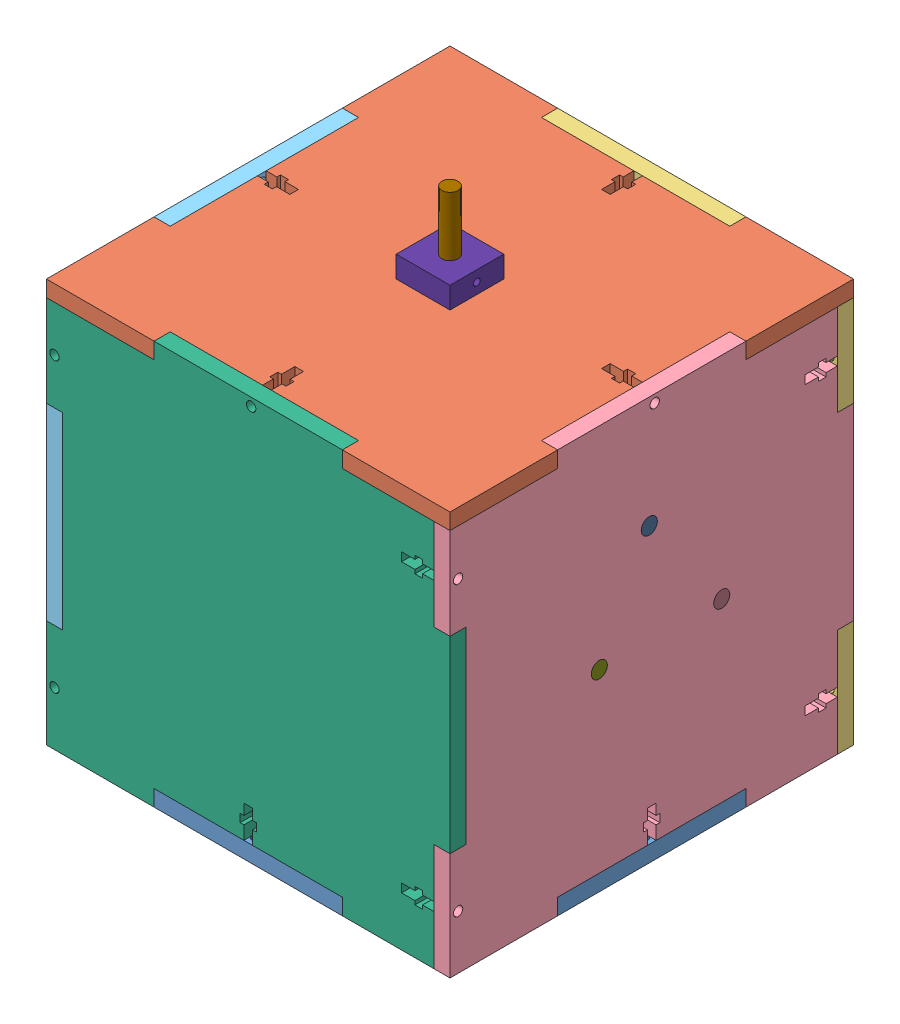
SolidWorks assembly Box_Assem, configuration Default. Lengths in mm.
Overall size (150 180 180).
35 component instances, 20 part files, 60 mates.
Components (placement in the parent):
- base-1: base [Default] at (64.477 69.4479 114.6209) size (150 6 150)
- lid-1: lid [Default] at (64.477 213.4479 114.6209) size (150 6 150)
- side_IN-1: side_IN [Default] at (67.477 141.4479 39.6209) size (150 150 6)
- side_3-1: side_3 [Default] at (139.477 141.4479 117.6209) x (0 0 1) z (-1 0 0) size (150 150 6)
- side_2-1: side_2 [Default] at (-10.523 141.4479 111.6209) x (0 0 -1) z (1 0 0) size (150 150 6)
- side_1-6: side_1 [Default] at (61.477 141.4479 189.6209) x (-1 0 0) z (0 0 -1) size (150 150 6)
- Part7^Box_Assem-1: Part7^Box_Assem [Default] at origin (virtual)
- Part9^Box_Assem-1: Part9^Box_Assem [Default] at origin (virtual)
- Assem5^Box_Assem-1: Assem5^Box_Assem [Default] at (178.5717 30.91 0) x (0.331384 0.943496 0) z (0 0 1) size (32.65 32.7 65.5) (virtual)
  - Input shaft-1: Input shaft [Default] at (-47.3106 246.4446 73.8642) x (-0.962325 0.271902 0) z (0 0 -1) size (6 6 64.24)
  - straight bevel pinion_am-1: straight bevel pinion_am [Metric - Straight bevel pinion 1.5M14PT 14GT 20PA 9FW ---14O75H20MD6N] at (67.477 141.4479 66.545) x (0 0 1) z (-0.653712 0.756744 0) size (16.5 22.92 23.41)
- Assem4^Box_Assem-1: Assem4^Box_Assem [Default] at (65.1602 0 246.1305) x (-0.874102 0 -0.485743) z (0.485743 0 -0.874102) size (29.77 58.5 29.46) (virtual)
  - output shaft^Assem4_Box_Assem-1: output shaft^Assem4_Box_Assem [Default] at (204.857 192.2046 181.6581) x (0.612932 0 0.790136) z (0 1 0) size (6 6 57.24) (virtual)
  - straight bevel pinion_am-1: straight bevel pinion_am [Metric - Straight bevel pinion 1.5M14PT 14GT 20PA 9FW ---14O75H20MD6N] at (64.477 199.5237 114.6209) x (0 -1 0) z (-0.94154 0 0.336902) size (16.5 22.92 23.41)
- Assem3^Box_Assem-1: Assem3^Box_Assem [Default] at (0 21.4454 258.8037) x (1 0 0) z (0 0.968014 0.250897) size (150 53.02 53.02) (virtual)
  - transmission shaft^Assem3_Box_Assem-1: transmission shaft^Assem3_Box_Assem [Default] at (-10.523 -19.5749 -105.5679) x (0 -0.566583 -0.824005) z (1 0 0) size (6 6 150) (virtual)
  - straight bevel gear_am-1: straight bevel gear_am [Metric - Straight bevel gear 1.5M 28GT 14PT 20PA 12FW ---28O32H20MD6N] at (77.5489 177.9396 115.5457) x (-1 0 0) z (0 0.275661 -0.961255) size (15.67 42.87 42.87)
  - spur gear_am-1: spur gear_am [Metric - Spur gear 1.5M 28T 20PA 7FW ---S28N75H50L6N] at (101.477 177.9396 115.5457) x (1 0 0) z (0 -0.000222 1) size (7 44.81 44.81)
- Assem2^Box_Assem-1: Assem2^Box_Assem [Default] at (0 307.1872 79.4315) x (1 0 0) z (0 -0.578194 -0.8159) size (150 70.86 71.34) (virtual)
  - Copy of Part12^Assem2_Box_Assem-1: Copy of Part12^Assem2_Box_Assem [Default] at (-10.523 144.6806 385.0821) x (0 -0.113895 0.993493) z (1 0 0) size (6 6 150) (virtual)
  - driving_gear-1: driving_gear [Default] at (21.477 185.0347 183.4062) x (0 0.8159 0.578194) z (0 -0.578194 0.8159) size (50 6 52)
  - straight bevel gear_am-1: straight bevel gear_am [Metric - Straight bevel gear 1.5M 28GT 14PT 20PA 12FW ---28O32H20MD6N] at (54.4051 140.9479 88.6209) x (1 0 0) z (0 -0.419052 0.907962) size (15.67 42.87 42.87)
- Assem1^Box_Assem-1: Assem1^Box_Assem [Default] at (0 321.0292 60.4632) x (1 0 0) z (0 -0.912292 -0.40954) size (150 61.88 61.88) (virtual)
  - driven_gear-1: driven_gear [Default] at (21.477 97.7558 8.8801) x (0 -0.40954 -0.912292) z (-1 0 0) size (41.67 41.75 6)
  - Copy of Part12^Assem1_Box_Assem-1: Copy of Part12^Assem1_Box_Assem [Default] at (-10.523 -73.8944 338.4392) x (0 -0.805923 0.59202) z (1 0 0) size (6 6 150) (virtual)
  - spur gear_am-1: spur gear_am [Metric - Spur gear 1.5M 28T 20PA 7FW ---S28N75H50L6N] at (101.477 140.9479 134.1209) x (1 0 0) z (0 -0.842968 -0.537964) size (7 44.81 44.81)
- Part13^Box_Assem-1: Part13^Box_Assem [Default] at origin (virtual)
- collar_6mm-1: collar_6mm [Default] at (230.1235 277.8142 31.6209) size (20 20 8)
- collar_6mm-2: collar_6mm [Default] at (227.1235 219.4479 -21.7454) x (1 0 0) z (0 1 0) size (20 20 8)
- collar_6mm-3: collar_6mm [Default] at (125.477 314.3059 -47.1009) x (0 0 -1) z (1 0 0) size (20 20 8)
- collar_6mm-4: collar_6mm [Default] at (125.477 -21.6987 -2.2454) x (0 -1 0) z (1 0 0) size (20 20 8)
- collar_6mm-5: collar_6mm [Default] at (125.477 303.5944 224.9872) x (0 1 0) z (1 0 0) size (20 20 8)
- collar_6mm-6: collar_6mm [Default] at (-4.523 314.3059 -47.1009) x (0 0 -1) z (1 0 0) size (20 20 8)
- collar_6mm-7: collar_6mm [Default] at (-4.523 303.5944 270.4872) x (0 1 0) z (1 0 0) size (20 20 8)
- collar_6mm-8: collar_6mm [Default] at (-4.523 303.5944 224.9872) x (0 1 0) z (1 0 0) size (20 20 8)
Mates (geometry in assembly coordinates):
- Coincident5: coincident aligned: plane of base-1 through (139.477 75.4479 114.6209) normal (1 0 0); plane of lid-1 through (139.477 219.4479 114.6209) normal (1 0 0)
- Coincident6: coincident aligned: plane of base-1 through (64.477 75.4479 189.6209) normal (0 0 1); plane of lid-1 through (64.477 219.4479 189.6209) normal (0 0 1)
- Coincident10: coincident anti-aligned: plane of lid-1 through (64.477 219.4479 45.6209) normal (0 0 -1); plane of side_IN-1 through (67.477 141.4479 45.6209) normal (0 0 1)
- Coincident11: coincident aligned: plane of lid-1 through (64.477 219.4479 114.6209) normal (0 1 0); plane of side_IN-1 through (67.477 219.4479 45.6209) normal (0 1 0)
- Coincident12: coincident aligned: plane of lid-1 through (139.477 219.4479 114.6209) normal (1 0 0); plane of side_IN-1 through (139.477 141.4479 45.6209) normal (1 0 0)
- Coincident16: coincident anti-aligned: plane of lid-1 through (133.477 219.4479 114.6209) normal (1 0 0); plane of side_3-1 through (133.477 141.4479 117.6209) normal (-1 0 0)
- Coincident17: coincident aligned: plane of lid-1 through (64.477 219.4479 114.6209) normal (0 1 0); plane of side_3-1 through (133.477 219.4479 117.6209) normal (0 1 0)
- Coincident18: coincident aligned: plane of side_IN-1 through (67.477 141.4479 39.6209) normal (0 0 -1); plane of side_3-1 through (133.477 141.4479 39.6209) normal (0 0 -1)
- Coincident19: coincident anti-aligned: plane of lid-1 through (-4.523 219.4479 114.6209) normal (-1 0 0); plane of side_2-1 through (-4.523 141.4479 111.6209) normal (1 0 0)
- Coincident20: coincident aligned: plane of side_IN-1 through (67.477 141.4479 39.6209) normal (0 0 -1); plane of side_2-1 through (-4.523 141.4479 39.6209) normal (0 0 -1)
- Coincident21: coincident aligned: plane of lid-1 through (64.477 219.4479 114.6209) normal (0 1 0); plane of side_2-1 through (-4.523 219.4479 111.6209) normal (0 1 0)
- Coincident26: coincident anti-aligned: plane of lid-1 through (64.477 219.4479 183.6209) normal (0 0 1); plane of side_1-6 through (61.477 141.4479 183.6209) normal (0 0 -1)
- Coincident27: coincident aligned: plane of side_3-1 through (139.477 141.4479 117.6209) normal (1 0 0); plane of side_1-6 through (139.477 141.4479 183.6209) normal (1 0 0)
- Coincident28: coincident aligned: plane of lid-1 through (64.477 219.4479 114.6209) normal (0 1 0); plane of side_1-6 through (61.477 219.4479 183.6209) normal (0 1 0)
- Distance16: distance = 112 mm: plane of Assem1^Box_Assem-1/driven_gear-1 through (21.477 140.9479 134.1209) normal (1 0 0); plane of side_3-1 through (133.477 141.4479 117.6209) normal (-1 0 0)
- Coincident60: coincident: plane of side_1-6 through (-10.523 141.4479 183.6209) normal (-1 0 0); plane of Assem1^Box_Assem-1/Copy of Part12^Assem1_Box_Assem-1 through (-10.523 140.9479 134.1209) normal (-1 0 0)
- Distance17: distance = 65.5 mm: cylinder of Assem1^Box_Assem-1/Copy of Part12^Assem1_Box_Assem-1 through (139.477 140.9479 134.1209) axis (-1 0 0) radius 3; plane of base-1 through (64.477 75.4479 114.6209) normal (0 1 0)
- Distance18: distance = 88.5 mm: cylinder of Assem1^Box_Assem-1/Copy of Part12^Assem1_Box_Assem-1 through (139.477 140.9479 134.1209) axis (-1 0 0) radius 3; plane of side_IN-1 through (67.477 141.4479 45.6209) normal (0 0 1)
- Distance19: distance = 25 mm anti-aligned: plane of Assem1^Box_Assem-1/spur gear_am-1 through (108.477 140.9479 134.1209) normal (1 0 0); plane of side_3-1 through (133.477 141.4479 117.6209) normal (-1 0 0)
- Coincident61: coincident: plane of side_IN-1 through (-10.523 141.4479 45.6209) normal (-1 0 0); plane of Assem2^Box_Assem-1/Copy of Part12^Assem2_Box_Assem-1 through (-10.523 140.9479 88.6209) normal (-1 0 0)
- Distance20: distance = 43 mm: cylinder of Assem2^Box_Assem-1/Copy of Part12^Assem2_Box_Assem-1 through (139.477 140.9479 88.6209) axis (-1 0 0) radius 3; plane of side_IN-1 through (67.477 141.4479 45.6209) normal (0 0 1)
- Distance21: distance = 65.5 mm: cylinder of Assem2^Box_Assem-1/Copy of Part12^Assem2_Box_Assem-1 through (139.477 140.9479 88.6209) axis (-1 0 0) radius 3; plane of base-1 through (64.477 75.4479 114.6209) normal (0 1 0)
- Distance22: distance = 112 mm: plane of side_3-1 through (133.477 141.4479 117.6209) normal (-1 0 0); plane of Assem2^Box_Assem-1/driving_gear-1 through (21.477 140.9479 88.6209) normal (1 0 0)
- Distance23: distance = 86 mm aligned: plane of Assem2^Box_Assem-1/straight bevel gear_am-1 through (47.477 140.9479 88.6209) normal (-1 0 0); plane of side_3-1 through (133.477 141.4479 117.6209) normal (-1 0 0)
- Coincident62: coincident: plane of side_1-6 through (-10.523 141.4479 183.6209) normal (-1 0 0); plane of Assem3^Box_Assem-1/Copy of Part12^Assem3_Box_Assem-1 through (-10.523 177.9396 115.5457) normal (-1 0 0)
- Coincident63: coincident: plane of side_IN-1 through (-10.523 141.4479 45.6209) normal (-1 0 0); plane of Assem3^Box_Assem-1/Copy of Part12^Assem3_Box_Assem-1 through (-10.523 177.9396 115.5457) normal (-1 0 0)
- Distance24: distance = 49 mm: plane of Assem3^Box_Assem-1/straight bevel gear_am-1 through (84.477 177.9396 115.5457) normal (1 0 0); plane of side_3-1 through (133.477 141.4479 117.6209) normal (-1 0 0)
- Distance25: distance = 25 mm anti-aligned: plane of Assem3^Box_Assem-1/spur gear_am-1 through (108.477 177.9396 115.5457) normal (1 0 0); plane of side_3-1 through (133.477 141.4479 117.6209) normal (-1 0 0)
- Concentric20: concentric aligned: cylinder of lid-1 through (64.477 219.4479 114.6209) axis (0 -1 0) radius 3; cylinder of Assem4^Box_Assem-1/Copy of Part10^Assem4_Box_Assem-1 through (64.477 249.4446 114.6209) axis (0 -1 0) radius 3
- Distance26: distance = 6 mm anti-aligned: plane of lid-1 through (64.477 213.4479 114.6209) normal (0 -1 0); plane of Assem4^Box_Assem-1/straight bevel pinion_am-1 through (64.477 207.4479 114.6209) normal (0 1 0)
- GearMate6: gear = 2 : 1 mm: circle of Assem4^Box_Assem-1/straight bevel pinion_am-1; circle of Assem3^Box_Assem-1/straight bevel gear_am-1
- Concentric21: concentric anti-aligned: cylinder of side_IN-1 through (67.477 141.4479 45.6209) axis (0 0 -1) radius 3; cylinder of Assem5^Box_Assem-1/Copy of Part10^Assem5_Box_Assem-1 through (67.477 141.4479 9.6242) axis (0 0 1) radius 3
- Distance27: distance = 13 mm anti-aligned: plane of side_IN-1 through (67.477 141.4479 45.6209) normal (0 0 1); plane of Assem5^Box_Assem-1/straight bevel pinion_am-1 through (67.477 141.4479 58.6209) normal (0 0 -1)
- GearMate7: gear = 1 : 2 mm: circle of Assem2^Box_Assem-1/straight bevel gear_am-1; circle of Assem5^Box_Assem-1/straight bevel pinion_am-1
- Concentric22: concentric aligned: cylinder of side_2-1 through (-4.523 177.9396 115.5457) axis (-1 0 0) radius 3; cylinder of Assem3^Box_Assem-1/Copy of Part12^Assem3_Box_Assem-1 through (139.477 177.9396 115.5457) axis (-1 0 0) radius 3
- GearMate8: gear = 6 : 6 mm: circle of Assem1^Box_Assem-1/spur gear_am-1; circle of Assem3^Box_Assem-1/spur gear_am-1
- Concentric23: concentric aligned: cylinder of Assem5^Box_Assem-1/Copy of Part10^Assem5_Box_Assem-1 through (67.477 141.4479 9.6242) axis (0 0 1) radius 3; cylinder of collar_6mm-1 through (67.477 141.4479 31.6209) axis (0 0 1) radius 3
- Coincident66: coincident anti-aligned: plane of side_IN-1 through (67.477 141.4479 39.6209) normal (0 0 -1); plane of collar_6mm-1 through (230.1235 277.8142 39.6209) normal (0 0 1)
- Parallel3: parallel aligned: plane of side_IN-1 through (-10.523 141.4479 45.6209) normal (-1 0 0); plane of collar_6mm-1 through (57.477 131.4479 39.6209) normal (-1 0 0)
- Coincident67: coincident anti-aligned: cylinder of Assem4^Box_Assem-1/Copy of Part10^Assem4_Box_Assem-1 through (64.477 249.4446 114.6209) axis (0 -1 0) radius 3; circle of collar_6mm-2
- Coincident68: coincident anti-aligned: plane of lid-1 through (64.477 219.4479 114.6209) normal (0 1 0); plane of collar_6mm-2 through (227.1235 219.4479 -21.7454) normal (0 -1 0)
- Parallel4: parallel aligned: plane of lid-1 through (-4.523 219.4479 114.6209) normal (-1 0 0); plane of collar_6mm-2 through (54.477 227.4479 124.6209) normal (-1 0 0)
- Coincident70: coincident anti-aligned: cylinder of Assem3^Box_Assem-1/Copy of Part12^Assem3_Box_Assem-1 through (139.477 177.9396 115.5457) axis (-1 0 0) radius 3; circle of collar_6mm-3
- Coincident71: coincident anti-aligned: plane of side_3-1 through (133.477 141.4479 117.6209) normal (-1 0 0); plane of collar_6mm-3 through (133.477 314.3059 -47.1009) normal (1 0 0)
- Parallel5: parallel anti-aligned: plane of side_1-6 through (61.477 141.4479 183.6209) normal (0 0 -1); plane of collar_6mm-3 through (133.477 167.9396 125.5457) normal (0 0 1)
- Coincident73: coincident anti-aligned: cylinder of Assem1^Box_Assem-1/Copy of Part12^Assem1_Box_Assem-1 through (139.477 140.9479 134.1209) axis (-1 0 0) radius 3; circle of collar_6mm-4
- Parallel6: parallel anti-aligned: plane of lid-1 through (64.477 213.4479 114.6209) normal (0 -1 0); plane of collar_6mm-4 through (133.477 150.9479 144.1209) normal (0 1 0)
- Coincident75: coincident anti-aligned: plane of side_3-1 through (133.477 141.4479 117.6209) normal (-1 0 0); plane of collar_6mm-4 through (133.477 -21.6987 -2.2454) normal (1 0 0)
- Coincident76: coincident anti-aligned: cylinder of Assem2^Box_Assem-1/Copy of Part12^Assem2_Box_Assem-1 through (139.477 140.9479 88.6209) axis (-1 0 0) radius 3; circle of collar_6mm-5
- Coincident77: coincident anti-aligned: plane of side_3-1 through (133.477 141.4479 117.6209) normal (-1 0 0); plane of collar_6mm-5 through (133.477 303.5944 224.9872) normal (1 0 0)
- Parallel7: parallel anti-aligned: plane of lid-1 through (64.477 213.4479 114.6209) normal (0 -1 0); plane of collar_6mm-5 through (133.477 150.9479 78.6209) normal (0 1 0)
- Coincident79: coincident anti-aligned: cylinder of Assem3^Box_Assem-1/Copy of Part12^Assem3_Box_Assem-1 through (139.477 177.9396 115.5457) axis (-1 0 0) radius 3; circle of collar_6mm-6
- Coincident82: coincident anti-aligned: plane of side_2-1 through (-4.523 141.4479 111.6209) normal (1 0 0); plane of collar_6mm-6 through (-4.523 314.3059 -47.1009) normal (-1 0 0)
- Parallel10: parallel anti-aligned: plane of side_IN-1 through (67.477 141.4479 45.6209) normal (0 0 1); plane of collar_6mm-6 through (3.477 167.9396 105.5457) normal (0 0 -1)
- Coincident84: coincident anti-aligned: cylinder of Assem2^Box_Assem-1/Copy of Part12^Assem2_Box_Assem-1 through (139.477 140.9479 88.6209) axis (-1 0 0) radius 3; circle of collar_6mm-8
- Coincident85: coincident anti-aligned: plane of side_2-1 through (-4.523 141.4479 111.6209) normal (1 0 0); plane of collar_6mm-8 through (-4.523 303.5944 224.9872) normal (-1 0 0)
- Parallel11: parallel anti-aligned: plane of lid-1 through (64.477 213.4479 114.6209) normal (0 -1 0); plane of collar_6mm-8 through (3.477 150.9479 78.6209) normal (0 1 0)
- Coincident87: coincident anti-aligned: cylinder of Assem1^Box_Assem-1/Copy of Part12^Assem1_Box_Assem-1 through (139.477 140.9479 134.1209) axis (-1 0 0) radius 3; circle of collar_6mm-7
- Coincident88: coincident anti-aligned: plane of side_2-1 through (-4.523 141.4479 111.6209) normal (1 0 0); plane of collar_6mm-7 through (-4.523 303.5944 270.4872) normal (-1 0 0)
- Parallel12: parallel anti-aligned: plane of lid-1 through (64.477 213.4479 114.6209) normal (0 -1 0); plane of collar_6mm-7 through (3.477 150.9479 124.1209) normal (0 1 0)
